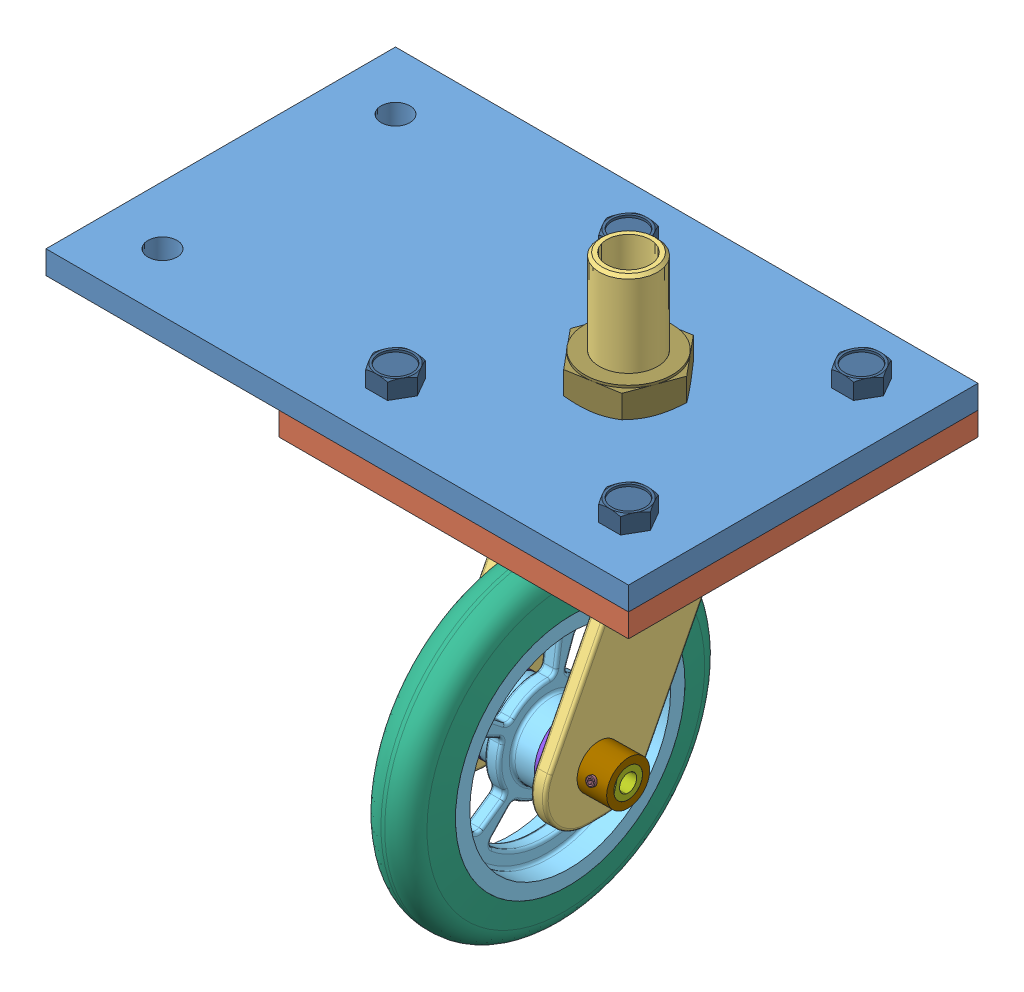
SolidWorks assembly Caster, configuration Default. Lengths in mm.
Overall size (200 194.22 158.32).
23 component instances, 13 part files, 19 mates.
Components (placement in the parent):
- Base-3: Base [Default] at (121.3735 -78.9245 111.3642) size (200 8 120)
- Mount-2: Mount [Default] at (171.0143 -86.9245 131.4776) size (120 8 120)
- Fork-1: Fork [Default] at (171.0143 -99.9245 131.4776) x (-0.014722 0 -0.999892) z (0.999892 0 -0.014722) size (89.6 143.34 80)
- Bearing-2: Bearing [Default] at (171.0143 -86.9245 131.4776) x (-0.132169 0 0.991227) z (0 -1 0) size (30 30 5)
- Wheel and Axle-1: Wheel and Axle [Default] at (214.5195 -130.2428 99.7428) x (-0.999892 0 0.014722) z (0.014265 0.247123 0.968879) size (60 110 110)
  - Wheel-1: Wheel [Default] at (43.5901 43.4624 52.9982) size (20 80 80)
  - Tire-1: Tire [Default] at (43.5901 43.4624 52.9982) x (0 0 -1) z (0 1 0) size (110 20 110)
  - Axle-2: Axle [Default] at (43.9894 43.4624 52.9982) x (0 1 0) z (-1 0 0) size (10 10 60)
  - Washer-2: Washer [Default] at (31.0901 43.4624 52.9982) size (5 25 25)
  - Washer-3: Washer [Default] at (56.4676 43.4624 52.9982) size (5 25 25)
- Collar-2: Collar [Default] at (196.468 -159.2601 162.1102) x (-0.003638 0.968984 -0.247096) z (-0.014265 -0.247123 -0.968879) size (15 10 15)
- Collar-5: Collar [Default] at (146.4735 -159.2601 162.8463) x (0.003638 -0.968984 0.247096) z (-0.014265 -0.247123 -0.968879) size (15 10 15)
- hex screw_am-8: hex screw_am [B18.6.7M - M8 x 1.25 x 25 Indented HHMS --25N] at (131.0143 -64.9245 171.4776) x (0 -1 0) z (0 0 1) size (31 15.01 13)
- hex nut style 1_am-4: hex nut style 1_am [B18.2.4.1M - Hex nut, Style 1,  M8 x 1.25 --D-N] at (131.0143 -86.9422 171.4776) x (-0.721884 0 0.692014) z (0 1 0) size (13 15.01 6.8)
- hex nut style 1_am-5: hex nut style 1_am [B18.2.4.1M - Hex nut, Style 1,  M8 x 1.25 --D-N] at (211.0143 -86.9422 91.4776) x (-0.721884 0 0.692014) z (0 1 0) size (13 15.01 6.8)
- hex nut style 1_am-6: hex nut style 1_am [B18.2.4.1M - Hex nut, Style 1,  M8 x 1.25 --D-N] at (131.0143 -86.9422 91.4776) x (-0.721884 0 0.692014) z (0 1 0) size (13 15.01 6.8)
- hex nut style 1_am-7: hex nut style 1_am [B18.2.4.1M - Hex nut, Style 1,  M8 x 1.25 --D-N] at (211.0143 -86.9422 171.4776) x (-0.721884 0 0.692014) z (0 1 0) size (13 15.01 6.8)
- hex screw_am-9: hex screw_am [B18.6.7M - M8 x 1.25 x 25 Indented HHMS --25N] at (211.0143 -64.9245 91.4776) x (0 -1 0) z (0 0 1) size (31 15.01 13)
- hex screw_am-10: hex screw_am [B18.6.7M - M8 x 1.25 x 25 Indented HHMS --25N] at (131.0143 -64.9245 91.4776) x (0 -1 0) z (0 0 1) size (31 15.01 13)
- hex screw_am-11: hex screw_am [B18.6.7M - M8 x 1.25 x 25 Indented HHMS --25N] at (211.0143 -64.9245 171.4776) x (0 -1 0) z (0 0 1) size (31 15.01 13)
- hex nut jam_am-1: hex nut jam_am [B18.2.4.5M - Hex jam nut,  M20 x 2.5 --W-N] at (171.0143 -70.9245 131.4776) x (0.769991 0 -0.638055) z (0 -1 0) size (30 34.64 10)
- socket set screw flat point_am-1: socket set screw flat point_am [B18.3.6M - M3 x 0.5 x 4 Hex Socket Flat Pt. SS --N] at (196.5893 -157.1596 170.3457) x (-0.014265 -0.247123 -0.968879) z (0.138911 0.959092 -0.246672) size (4 3 3)
- socket set screw flat point_am-2: socket set screw flat point_am [B18.3.6M - M3 x 0.5 x 4 Hex Socket Flat Pt. SS --N] at (146.5947 -157.1596 171.0818) x (-0.014265 -0.247123 -0.968879) z (0.70064 0.688842 -0.186012) size (4 3 3)
Mates (geometry in assembly coordinates):
- Coincident18: coincident anti-aligned: circle of Base-3; circle of Mount-2
- Coincident19: coincident anti-aligned: plane of Fork-1 through (171.0143 -91.9245 131.4776) normal (0 1 0); circle of Bearing-2
- Concentric7: concentric aligned: circle of Mount-2; circle of Bearing-2
- Coincident20: coincident anti-aligned: circle of Fork-1; circle of Wheel and Axle-1/Washer-3
- Parallel4: parallel anti-aligned: plane of Wheel and Axle-1/Axle-2 through (191.5189 -160.2599 167.0826) normal (0.014265 0.247123 0.968879); plane of Collar-2 through (196.468 -159.2601 162.1102) normal (-0.014265 -0.247123 -0.968879)
- Coincident22: coincident anti-aligned: circle of Fork-1; circle of Collar-2
- Coincident45: coincident aligned: circle of Fork-1; circle of Collar-5
- Concentric11: concentric aligned: cylinder of Base-3 through (131.0143 -78.9245 171.4776) axis (0 1 0) radius 5; cylinder of hex screw_am-8 through (131.0143 -39.5245 171.4776) axis (0 1 0) radius 4
- Coincident46: coincident anti-aligned: plane of Base-3 through (121.3735 -70.9245 111.3642) normal (0 1 0); plane of hex screw_am-8 through (135.0143 -70.9245 171.4776) normal (0 -1 0)
- Concentric19: concentric aligned: cylinder of hex screw_am-8 through (131.0143 -39.5245 171.4776) axis (0 1 0) radius 4; cylinder of hex nut style 1_am-4 through (131.0143 -111.9797 171.4776) axis (0 1 0) radius 4
- Concentric20: concentric anti-aligned: circle of Mount-2; circle of hex nut style 1_am-4
- Concentric21: concentric aligned: cylinder of Fork-1 through (171.0143 -31.9245 131.4776) axis (0 -1 0) radius 10; cylinder of hex nut jam_am-1 through (171.0143 -45.887 131.4776) axis (0 -1 0) radius 10
- Coincident51: coincident anti-aligned: plane of Base-3 through (121.3735 -70.9245 111.3642) normal (0 1 0); plane of hex nut jam_am-1 through (182.0657 -70.9245 144.8142) normal (0 -1 0)
- Concentric25: concentric anti-aligned: cylinder of Collar-5 through (146.5805 -157.4064 170.1139) axis (-0.014265 -0.247123 -0.968879) radius 1.5; cylinder of socket set screw flat point_am-2 through (146.7759 -154.0211 183.3865) axis (0.014265 0.247123 0.968879) radius 1.5
- Coincident54: coincident anti-aligned: plane of Wheel and Axle-1/Axle-2 through (151.5232 -160.2599 167.6715) normal (0.014265 0.247123 0.968879); plane of socket set screw flat point_am-2 through (145.8243 -157.4666 167.0429) normal (-0.014265 -0.247123 -0.968879)
- Coincident56: coincident anti-aligned: plane of Mount-2 through (171.0143 -86.9245 131.4776) normal (0 -1 0); plane of Bearing-2 through (171.0143 -86.9245 131.4776) normal (0 1 0)
- Concentric26: concentric aligned: cylinder of Base-3 through (171.0143 -28.9245 131.4776) axis (0 -1 0) radius 12.5; cylinder of Fork-1 through (171.0143 -31.9245 131.4776) axis (0 -1 0) radius 10
- Concentric28: concentric anti-aligned: cylinder of Collar-2 through (196.575 -157.4064 169.3778) axis (-0.014265 -0.247123 -0.968879) radius 1.5; cylinder of socket set screw flat point_am-1 through (196.7705 -154.0211 182.6505) axis (0.014265 0.247123 0.968879) radius 1.5
- Coincident60: coincident anti-aligned: plane of Wheel and Axle-1/Axle-2 through (191.5189 -160.2599 167.0826) normal (0.014265 0.247123 0.968879); plane of socket set screw flat point_am-1 through (195.542 -158.0099 166.4495) normal (-0.014265 -0.247123 -0.968879)
